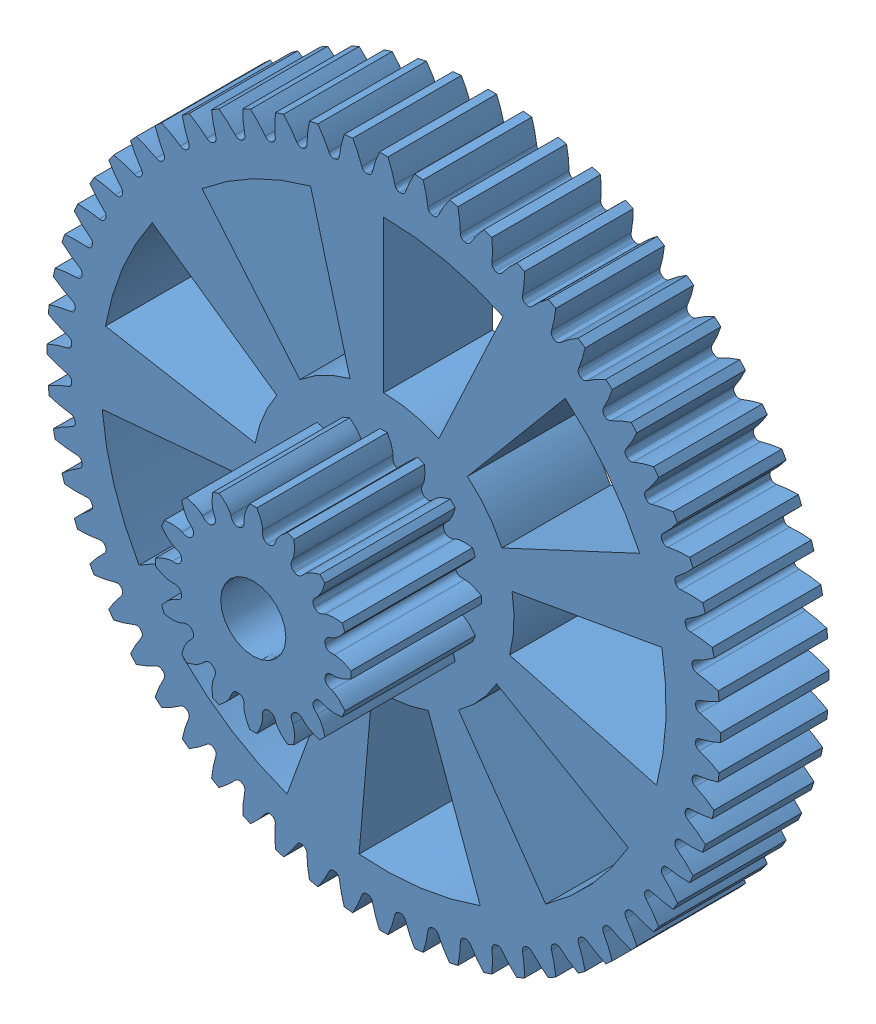
SolidWorks assembly 16-60t gear, configuration Default. Lengths in mm.
Overall size (31 31 11).
3 component instances, 3 part files, 2 mates.
Components (placement in the parent):
- 16T 3mm bore-1: 16T 3mm bore [Gear Blank] at (-4.1344 13.2481 -9.3189) size (9 9 6) (hidden)
- 60T 30mm-2: 60T 30mm [Gear Blank] at (-4.1344 13.2481 -15.3189) size (31 31 5) (hidden)
- 16-60 dual gear (6mm)-1: 16-60 dual gear (6mm) [Default] at origin size (31 31 11)
Mates (geometry in assembly coordinates):
- Concentric1: concentric aligned: cylinder of 16T 3mm bore-1 through (-4.1344 13.2481 -4.3189) axis (0 0 -1) radius 1.5; cylinder of 60T 30mm-2 through (-4.1344 13.2481 -10.3189) axis (0 0 -1) radius 3
- Coincident1: coincident anti-aligned: plane of 16T 3mm bore-1 through (-4.4228 17.5162 -10.3189) normal (0 0 -1); plane of 60T 30mm-2 through (-4.4357 28.4951 -10.3189) normal (0 0 1)
